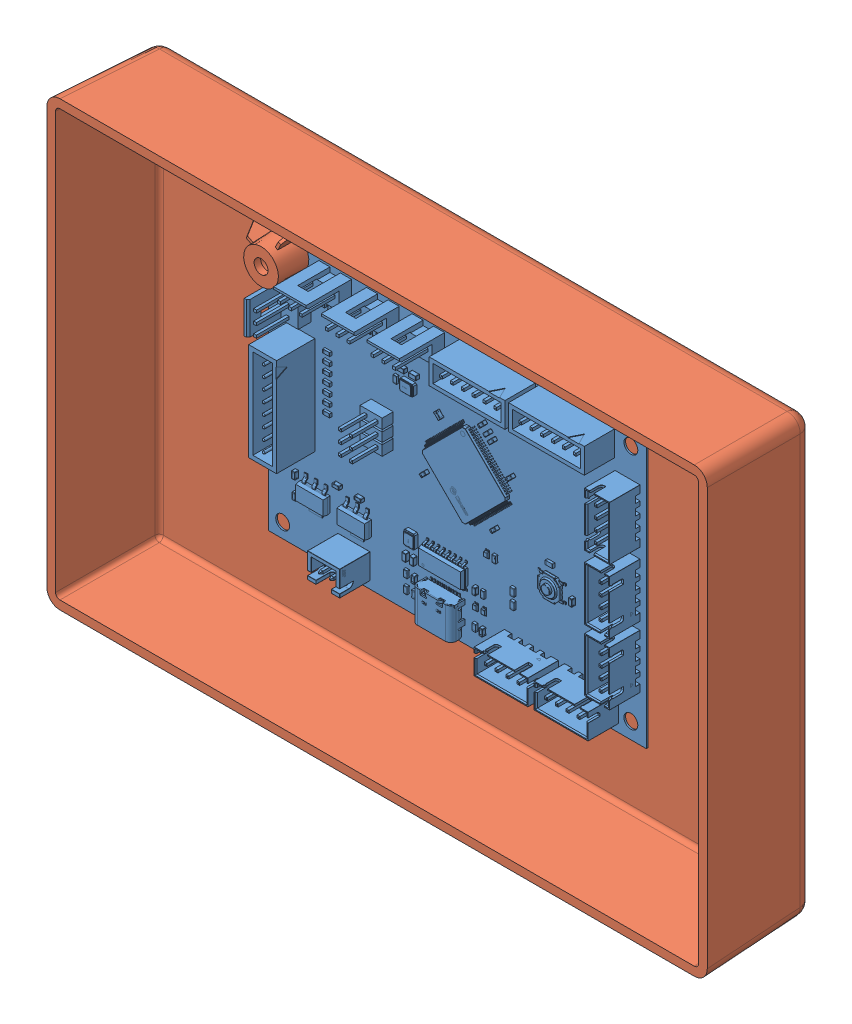
SolidWorks assembly Assem1, configuration Default. Lengths in mm.
Overall size (151.75 101.75 25).
2 component instances, 2 part files, 4 mates.
Components (placement in the parent):
- PCB.step-1: PCB.step [Default] at (-32.2883 -17.2714 61.5825) size (86.87 62.1 14)
- Part2^PCB box-1: Part2^PCB box [Default] at (0 0 54.5825) size (151.75 101.75 25) (virtual)
Mates (geometry in assembly coordinates):
- InPlace1: in place: plane of Part2^PCB box-1 through (0 0 54.5825) normal (0 0 1); moOrthogonalPlaneRef_w of Part2^PCB box-1 through (0 0 54.5825) normal (0 1 0); plane of Part2^PCB box-1 through (0 0 54.5825) normal (1 0 0); unknown of Part2^PCB box-1
- Coincident1: coincident aligned: 
- Coincident2: coincident aligned: plane of Part2^Assem1-1 through (0 0 54.5825) normal (0 1 0)
- Coincident3: coincident anti-aligned: plane of Part2^Assem1-1 through (0 0 54.5825) normal (1 0 0)
